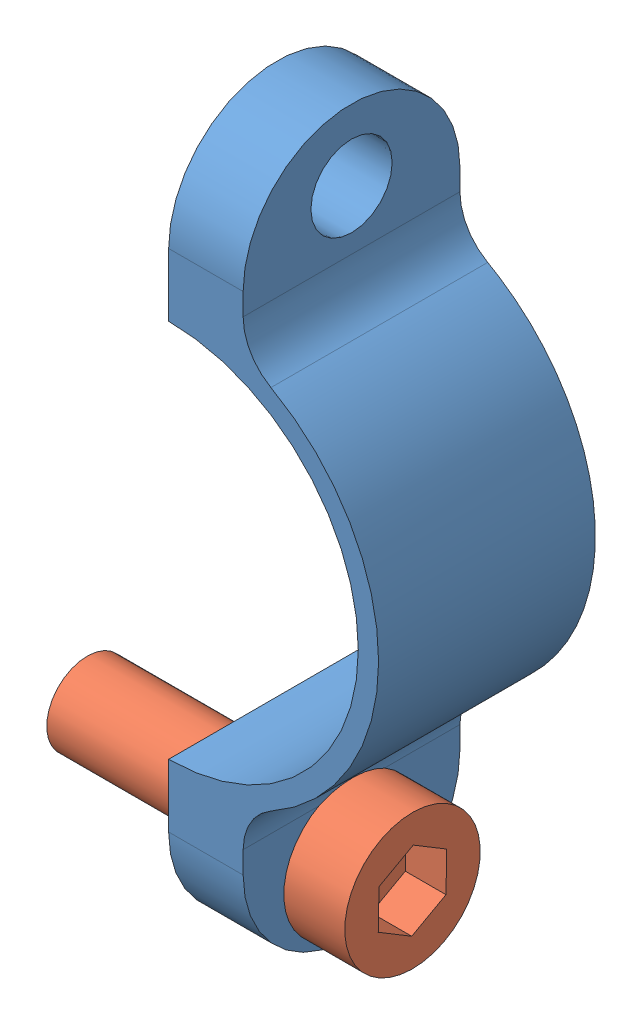
SolidWorks assembly PUTM-S-SR-RB_bearing_mount_assembly, configuration Domyślna. Lengths in mm.
Overall size (29.5 53.3 16).
3 component instances, 3 part files, 2 mates.
Components (placement in the parent):
- PUTM-S-SR-RB-bearing_mount-1: PUTM-S-SR-RB-bearing_mount [Domyślna] at (-0.5 -47.6728 -8) size (15.5 53.3 16)
- PUTM-S-SR-RB-bearing_mount_low-1: PUTM-S-SR-RB-bearing_mount_low [Domyślna] at (0 -47.6728 0) x (0 1 0) z (0 0 -1) (suppressed, hidden)
- PUTM-S-SR-RB-Bolt-2: PUTM-S-SR-RB-Bolt [Domyślna] at (9.5 -69.0728 0) x (0 -0.0195 -0.99981) z (0 -0.99981 0.0195) size (10 24 10)
Mates (geometry in assembly coordinates):
- Wspólnie13: coincident: plane of PUTM-S-SR-RB-bearing_mount_low-1 through (0 -47.6728 0) normal (0 0 -1); plane of assembly through (0 0 0) normal (0 0 1)
- Wspólnie14: coincident: plane of PUTM-S-SR-RB-bearing_mount_low-1 through (0 -47.6728 0) normal (1 0 0); plane of assembly through (0 0 0) normal (1 0 0)
